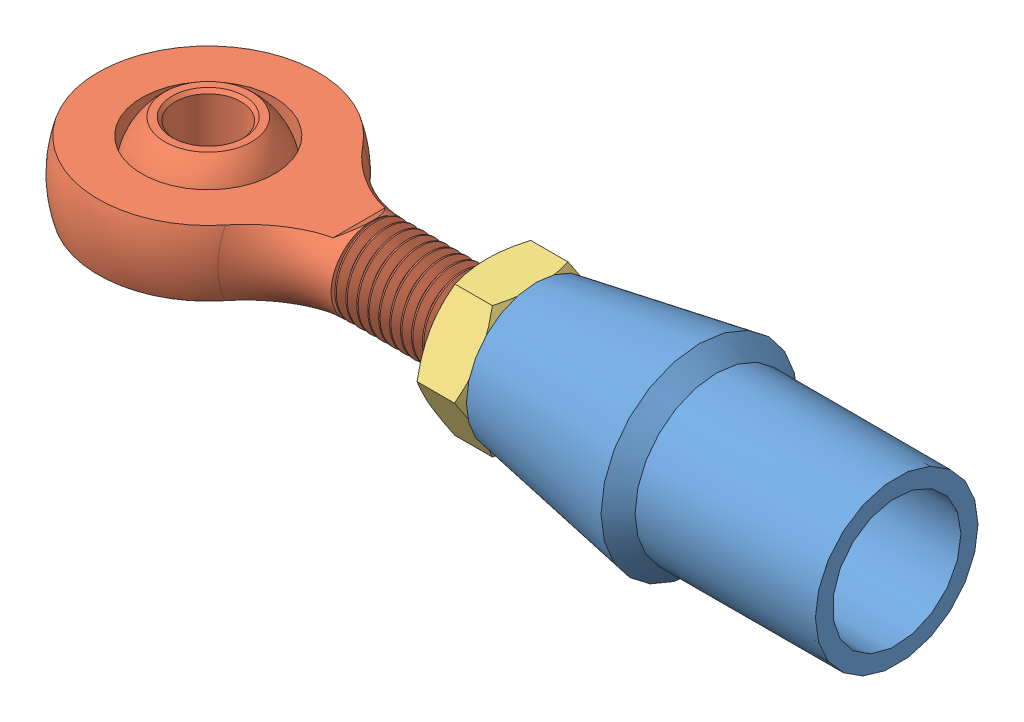
SolidWorks assembly FS2-SU-A-0002-R, RIGHT HAND ROD END TUBE END ASSEMBLY, configuration Default. Lengths in mm.
Overall size (77.79 19.05 22.23).
3 component instances, 3 part files, 9 mates.
Components (placement in the parent):
- TUBE-END WELD NUT, Right Hand 0.3125-24 0.75 TUBE 0.065 WALL, 94640A110, MMC-1: TUBE-END WELD NUT, Right Hand 0.3125-24 0.75 TUBE 0.065 WALL, 94640A110, MMC [94640A110] x (0 1 0) z (0 0 1) size (19.05 35.46 19.05)
- ROD END, STEEL BALL JOINT ID 0.25 0.3125-24 Right-Hand, 60645K822, MMC-1: ROD END, STEEL BALL JOINT ID 0.25 0.3125-24 Right-Hand, 60645K822, MMC [60645K822] at (-33.3375 0 0) x (0 0 -1) z (0 1 0) size (22.23 58.96 9.53)
- THIN HEX NUT, 0.3125-24 GRADE 5 STEEL , 94846A510, MMC-1: THIN HEX NUT, 0.3125-24 GRADE 5 STEEL , 94846A510, MMC [94846A510] at (-19.8438 0 0) x (0 -1 0) z (0 0 1) size (12.7 5.58 14.66)
Mates (geometry in assembly coordinates):
- Coincident1: coincident anti-aligned: plane of TUBE-END WELD NUT, 0.3125-24 0.75 TUBE 0.065 WALL, 94640A110, MMC-1 through (0 0 0) normal (-1 0 0)
- Coincident2: coincident aligned: plane of TUBE-END WELD NUT, 0.3125-24 0.75 TUBE 0.065 WALL, 94640A110, MMC-1 through (0 0 0) normal (0 0 1)
- Coincident3: coincident aligned: plane of TUBE-END WELD NUT, 0.3125-24 0.75 TUBE 0.065 WALL, 94640A110, MMC-1 through (0 0 0) normal (0 1 0)
- Coincident4: coincident aligned: line of ROD END, STEEL BALL JOINT 0.3125-24 Right-Hand, 60645K822, MMC-1 through (31.75 -1.5875 0) axis (0 -1 0)
- Parallel1: parallel anti-aligned: plane of ROD END, STEEL BALL JOINT 0.3125-24 Right-Hand, 60645K822, MMC-1 through (-60.325 -3.175 11.1125) normal (0 -1 0)
- Parallel2: parallel anti-aligned: plane of THIN HEX NUT, 0.3125-24 GRADE 5 STEEL , 94846A510, MMC-1 through (-17.4625 -6.35 3.6662) normal (0 -1 0)
- Coincident9: coincident anti-aligned: plane of TUBE-END WELD NUT, 0.3125-24 0.75 TUBE 0.065 WALL, 94640A110, MMC-1 through (-17.4625 -3.9688 0) normal (-1 0 0); plane of THIN HEX NUT, 0.3125-24 GRADE 5 STEEL , 94846A510, MMC-1 through (-17.4625 6.35 -3.6662) normal (1 0 0)
- Coincident11: coincident: point of THIN HEX NUT, 0.3125-24 GRADE 5 STEEL , 94846A510, MMC-1
- Distance1: distance = 11.1125 mm anti-aligned: plane of ROD END, STEEL BALL JOINT 0.3125-24 Right-Hand, 60645K822, MMC-1 through (-33.3375 0 -3.9751) normal (1 0 0); plane of THIN HEX NUT, 0.3125-24 GRADE 5 STEEL , 94846A510, MMC-1 through (-22.225 6.35 -3.6662) normal (-1 0 0)
